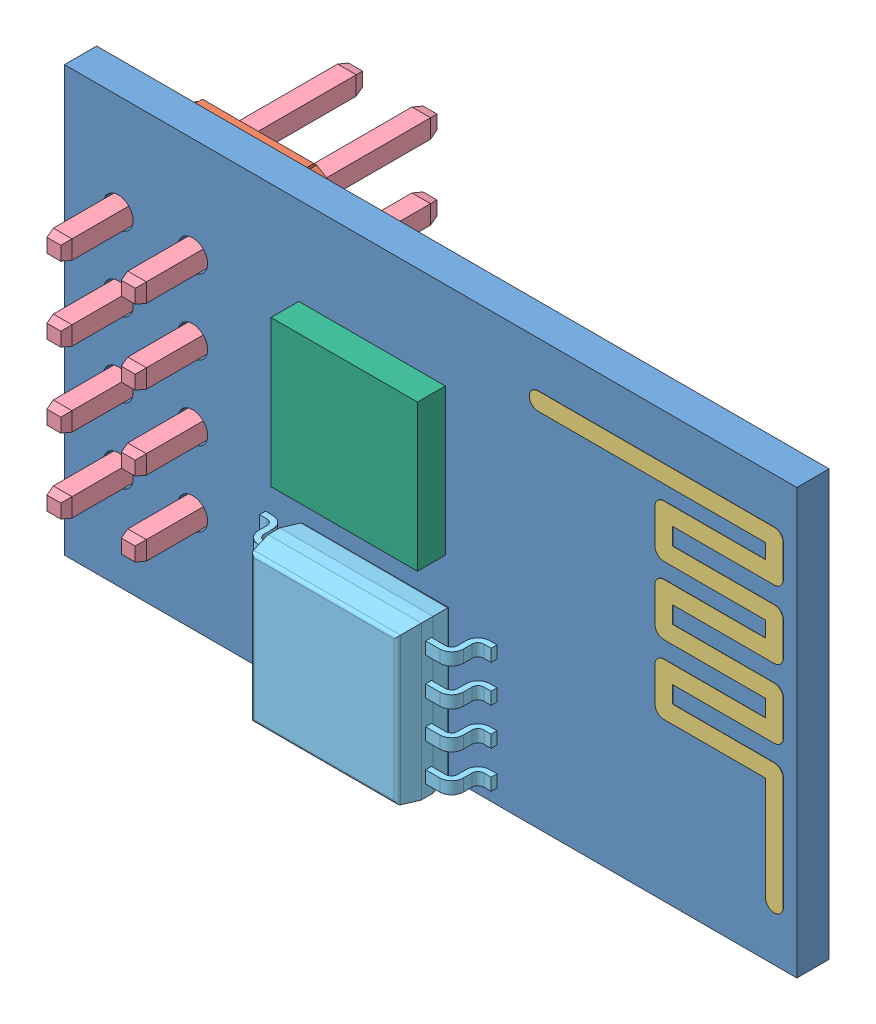
SolidWorks assembly WI, configuration Predeterminado. Lengths in mm.
Overall size (25 14.5 10.3).
14 component instances, 6 part files, 0 mates.
Components (placement in the parent):
- ESP8266-ESP01.stp-1: ESP8266-ESP01.stp [Predeterminado] at origin size (25 14.5 10.3)
  - Platine.stp-1: Platine.stp [Predeterminado] at origin size (25 14.5 1.1)
  - PinSockel.stp-1: PinSockel.stp [Predeterminado] at (1.8391 11.06 0) x (1 0 0) z (0 0 -1) size (5 10.16 2.5)
  - PCB_Antenna.stp-1: PCB_Antenna.stp [Predeterminado] at (1 16 0.81) x (0 -1 0) z (-1 0 0) size (11.4 0.04 8.67)
  - Pin_Stiftleiste.stp-1: Pin_Stiftleiste.stp [Predeterminado] at (1.8391 3.44 0) x (-1 0 0) z (0 0 -1) size (0.64 0.64 10.3)
  - Pin_Stiftleiste.stp-2: Pin_Stiftleiste.stp [Predeterminado] at (4.3791 3.44 0) x (-1 0 0) z (0 0 -1) size (0.64 0.64 10.3)
  - Pin_Stiftleiste.stp-3: Pin_Stiftleiste.stp [Predeterminado] at (1.8391 5.98 0) x (-1 0 0) z (0 0 -1) size (0.64 0.64 10.3)
  - Pin_Stiftleiste.stp-4: Pin_Stiftleiste.stp [Predeterminado] at (4.3791 5.98 0) x (-1 0 0) z (0 0 -1) size (0.64 0.64 10.3)
  - Pin_Stiftleiste.stp-5: Pin_Stiftleiste.stp [Predeterminado] at (1.8391 8.52 0) x (-1 0 0) z (0 0 -1) size (0.64 0.64 10.3)
  - Pin_Stiftleiste.stp-6: Pin_Stiftleiste.stp [Predeterminado] at (4.3791 8.52 0) x (-1 0 0) z (0 0 -1) size (0.64 0.64 10.3)
  - Pin_Stiftleiste.stp-7: Pin_Stiftleiste.stp [Predeterminado] at (1.8391 11.06 0) x (-1 0 0) z (0 0 -1) size (0.64 0.64 10.3)
  - Pin_Stiftleiste.stp-8: Pin_Stiftleiste.stp [Predeterminado] at (4.3791 11.06 0) x (-1 0 0) z (0 0 -1) size (0.64 0.64 10.3)
  - SerialFlashMem.stp-1: SerialFlashMem.stp [Predeterminado] at (8.2 0.1 1.1) size (7.9 5.23 1.97)
  - ESP8266EX.stp-1: ESP8266EX.stp [Predeterminado] at (8 6.5 1.1) size (5 5 0.95)
